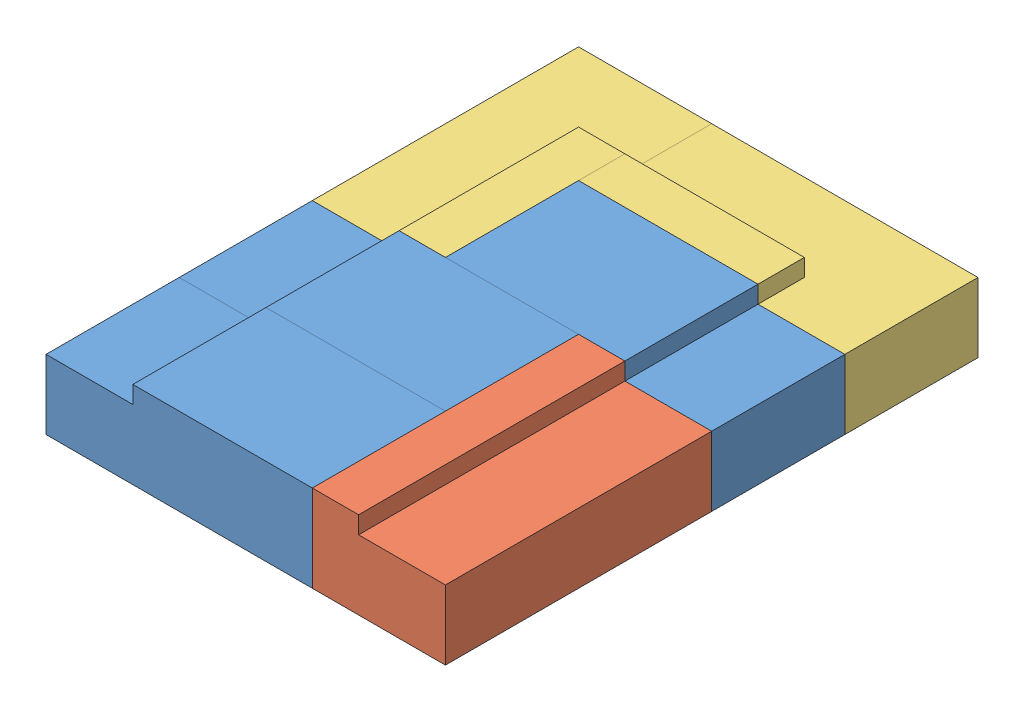
SolidWorks assembly Heat Treat Asm Top-Bot Alt Long, configuration Default. Lengths in mm.
Overall size (345 75 460).
6 component instances, 3 part files, 12 mates.
Components (placement in the parent):
- Brick-Sharp-BackCut-1: Brick-Sharp-BackCut [Default] at (102.0414 124.8114 164.7515) size (230 75 115)
- Brick-Sharp-SideCut-1: Brick-Sharp-SideCut [Default] at (274.5414 124.8114 107.2515) x (0 0 1) z (-1 0 0) size (230 75 115)
- Brick-Sharp-BackCut-2: Brick-Sharp-BackCut [Default] at (102.0414 124.8114 49.7515) size (230 75 115)
- Brick-Sharp-BackCut-3: Brick-Sharp-BackCut [Default] at (217.0414 124.8114 -65.2485) x (-1 0 0) z (0 0 -1) size (230 75 115)
- Brick-Sharp-BackLeftCut-2: Brick-Sharp-BackLeftCut [Default] at (217.0414 124.8114 -180.2485) x (-1 0 0) z (0 0 -1) size (230 75 115)
- Brick-Sharp-BackLeftCut-3: Brick-Sharp-BackLeftCut [Default] at (44.5414 124.8114 -122.7485) x (0 0 1) z (-1 0 0) size (230 75 115)
Mates (geometry in assembly coordinates):
- Coincident1: coincident anti-aligned: plane of Brick-Sharp-BackCut-1 through (217.0414 162.3114 107.2515) normal (1 0 0); plane of Brick-Sharp-SideCut-1 through (217.0414 162.3114 -7.7485) normal (-1 0 0)
- Coincident2: coincident aligned: line of Brick-Sharp-BackCut-1 through (217.0414 162.3114 222.2515) axis (0 -1 0); line of Brick-Sharp-SideCut-1 through (217.0414 162.3114 222.2515) axis (0 -1 0)
- Coincident3: coincident anti-aligned: line of Brick-Sharp-BackCut-1 through (217.0414 162.3114 222.2515) axis (0 0 -1); line of Brick-Sharp-SideCut-1 through (217.0414 162.3114 -7.7485) axis (0 0 1)
- Coincident4: coincident: plane of Brick-Sharp-SideCut-1 through (332.0414 162.3114 -7.7485) normal (0 0 -1); plane of Brick-Sharp-BackCut-3 through (332.0414 162.3114 -7.7485) normal (0 0 1)
- Coincident5: coincident: line of Brick-Sharp-SideCut-1 through (332.0414 147.3114 -7.7485) axis (0 -1 0); line of Brick-Sharp-BackCut-3 through (332.0414 147.3114 -7.7485) axis (0 -1 0)
- Coincident6: coincident anti-aligned: line of Brick-Sharp-SideCut-1 through (332.0414 87.3114 -7.7485) axis (-1 0 0); line of Brick-Sharp-BackCut-3 through (102.0414 87.3114 -7.7485) axis (1 0 0)
- Coincident7: coincident: plane of Brick-Sharp-BackCut-3 through (332.0414 162.3114 -122.7485) normal (0 0 -1); plane of Brick-Sharp-BackLeftCut-2 through (332.0414 162.3114 -122.7485) normal (0 0 1)
- Coincident8: coincident: line of Brick-Sharp-BackCut-3 through (332.0414 147.3114 -122.7485) axis (0 -1 0); line of Brick-Sharp-BackLeftCut-2 through (332.0414 147.3114 -122.7485) axis (0 -1 0)
- Coincident9: coincident anti-aligned: line of Brick-Sharp-BackCut-3 through (332.0414 87.3114 -122.7485) axis (-1 0 0); line of Brick-Sharp-BackLeftCut-2 through (102.0414 87.3114 -122.7485) axis (1 0 0)
- Coincident10: coincident: plane of Brick-Sharp-BackCut-2 through (-12.9586 162.3114 -7.7485) normal (0 0 -1); plane of Brick-Sharp-BackLeftCut-3 through (102.0414 162.3114 -7.7485) normal (0 0 1)
- Coincident11: coincident: plane of Brick-Sharp-BackLeftCut-2 through (102.0414 162.3114 -122.7485) normal (-1 0 0); plane of Brick-Sharp-BackLeftCut-3 through (102.0414 162.3114 -237.7485) normal (1 0 0)
- Coincident12: coincident anti-aligned: line of Brick-Sharp-BackCut-3 through (102.0414 162.3114 -122.7485) axis (0 0 1); line of Brick-Sharp-BackLeftCut-3 through (102.0414 162.3114 -7.7485) axis (0 0 -1)
